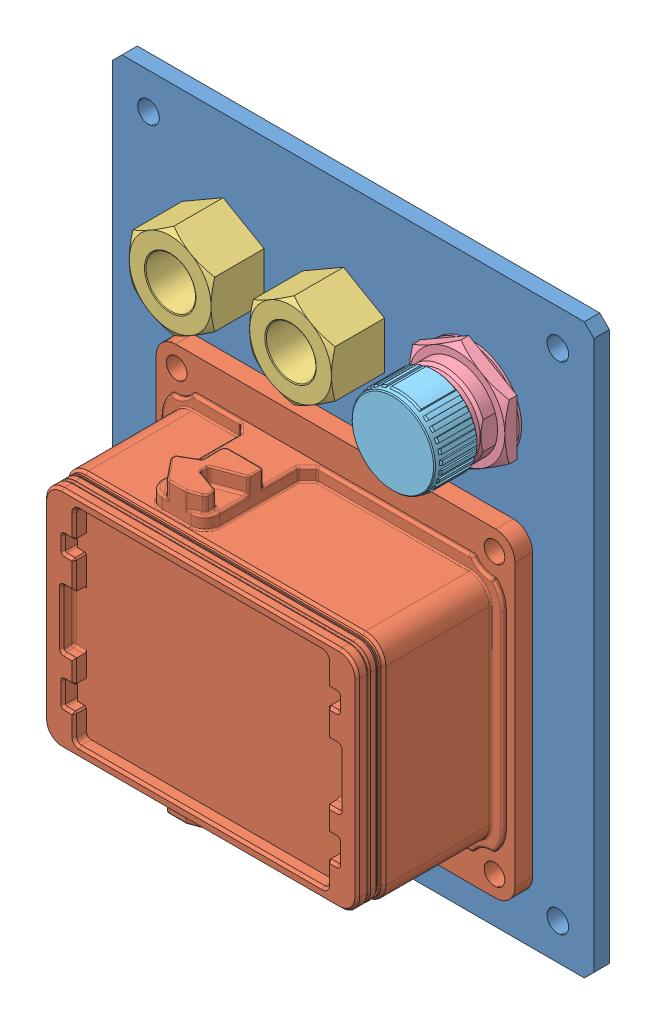
SolidWorks assembly C_BASE_ASSEMBLY_ASM, configuration Default. Lengths in mm.
Overall size (100 118 48.69).
6 component instances, 5 part files, 2 mates.
Components (placement in the parent):
- C_BASE-1: C_BASE [Default] at origin size (100 118 3.2)
- connector-1: connector [Default] at (0 -17 4.4) x (0 -1 0) z (0 0 -1) size (66.4 74.5 42.53)
- AirInlet-1: AirInlet [Default] at (-27 34 1.4) x (0 0 -1) z (0 1 0) size (28 17 19.63)
- LF13WBRB-20P-1: LF13WBRB-20P [Default] at (25 34 17.1) x (0 0 -1) z (1 0 0) size (19.25 23.09 21.5)
- LF13WBR-C-1: LF13WBR-C [Default] at (25 34 12.35) x (0 0 1) z (0 1 0) size (8.8 17.9 17.9)
- AirInlet-3: AirInlet [Default] at (-2 34 1.4) x (0 0 -1) z (0 1 0) size (28 17 19.63)
Mates (geometry in assembly coordinates):
- Concentric1: concentric aligned: cylinder of C_BASE-1 through (-2 34 4.4) axis (0 0 -1) radius 7.5; cylinder of AirInlet-3 through (-2 34 21.199) axis (0 0 -1) radius 7
- Coincident1: coincident: plane of KQ2E06-02-1 through (-27 34 15.4) normal (0 0 1); plane of KQ2E06-02-3 through (-6.2613 34.4749 4.4) normal (0 0 1)
